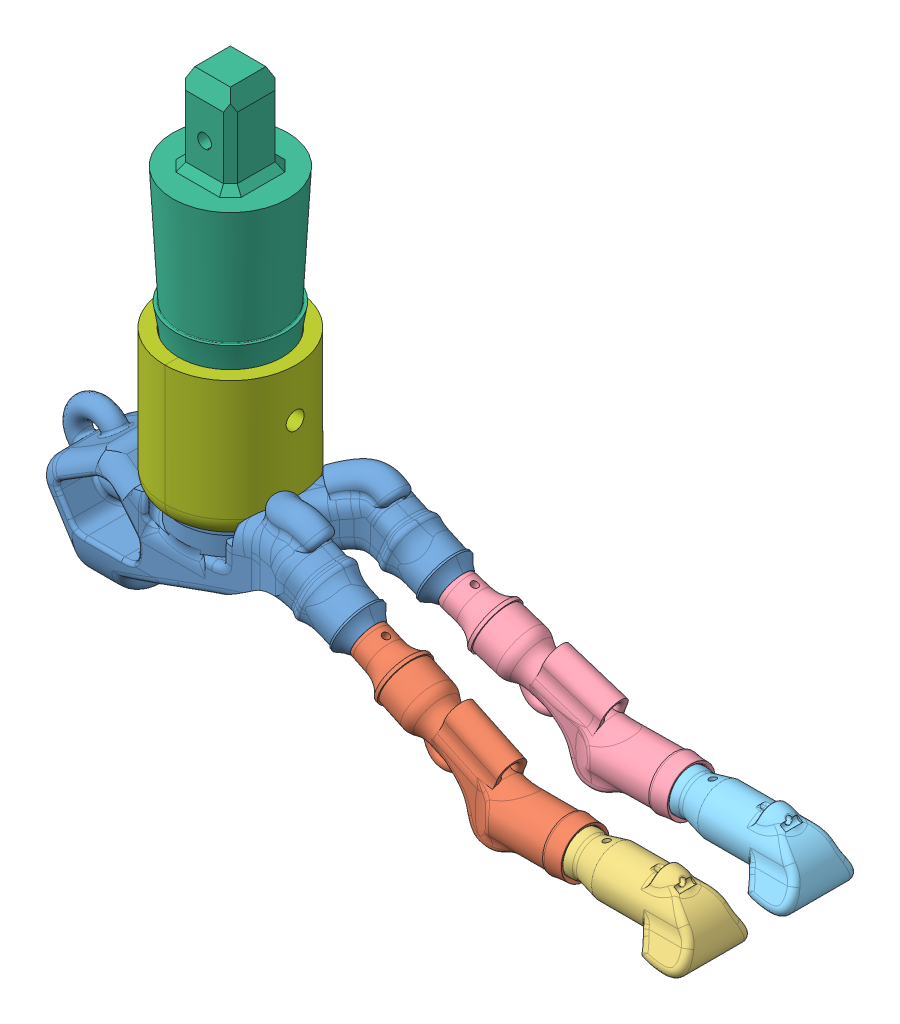
SolidWorks assembly Foot, configuration Default. Lengths in mm.
Overall size (260.5 189.24 79.33).
8 component instances, 7 part files, 12 mates.
Components (placement in the parent):
- Talus - New-1: Talus - New [Default] at origin size (131.32 65.14 51)
- Metatarsals-1: Metatarsals [Default] at (104.0952 -44.3034 18.1531) x (-0.929116 0.366544 -0.048875) z (0.042994 -0.024198 -0.998782) size (95.04 30.95 38.02)
- Phalanges-1: Phalanges [Default] at (172.2396 -55.1541 19.5999) size (57.16 24.44 28.69)
- Metatarsals - Left side-1: Metatarsals - Left side [Default] at (104.1326 -44.2161 -17.9587) x (-0.930097 0.364252 0.047332) z (-0.050841 -0.000045 -0.998707) size (95.04 30.95 38.02)
- Phalanges - Left side-1: Phalanges - Left side [Default] at (172.3053 -54.9301 -19.5095) size (57.16 24.44 28.69)
- Tibial End-1: Tibial End [Default] at (0 -22 0) x (0 0 1) z (-1 0 0) size (42.45 113.08 48.21)
- Sleeve-4: Sleeve [Default] at (0 -22.86 0) x (-1 0 0) z (0 0 -1) size (26.42 52.07 48.26)
- Sleeve-5: Sleeve [Default] at (0 -22.86 0) size (26.42 52.07 48.26)
Mates (geometry in assembly coordinates):
- Concentric1: concentric: sphere of Metatarsals-1; sphere of Talus - New-1
- Concentric2: concentric: sphere of Phalanges-1; sphere of Metatarsals-1
- Concentric3: concentric: sphere of Talus - New-1; sphere of Metatarsals - Left side-1
- Concentric4: concentric: sphere of Phalanges - Left side-1; sphere of Metatarsals - Left side-1
- Parallel4: parallel aligned: plane of Talus - New-1 through (0 0 17.78) normal (0 0 1); plane of Tibial End-1 through (-9.525 111.35 9.525) normal (0 0 1)
- LimitAngle3: limit planar angle = 1.570796 rad anti-aligned: plane of Tibial End-1 through (9.525 111.35 9.525) normal (1 0 0); plane of assembly through (0 0 0) normal (0 1 0)
- Concentric5: concentric aligned: cylinder of Tibial End-1 through (21.1996 10.2589 0) axis (-1 0 0) radius 3.302; cylinder of Sleeve-5 through (38.608 10.2589 0) axis (-1 0 0) radius 3.302
- Coincident13: coincident aligned: plane of Sleeve-4 through (0 27.94 0) normal (0 1 0); plane of Sleeve-5 through (0 27.94 0) normal (0 1 0)
- Concentric6: concentric anti-aligned: circle of Tibial End-1; circle of Sleeve-5
- Coincident15: coincident anti-aligned: plane of Sleeve-4 through (0 -22.86 0) normal (1 0 0); plane of Sleeve-5 through (0 -22.86 0) normal (-1 0 0)
- Concentric7: concentric anti-aligned: circle of Talus - New-1; circle of Tibial End-1
- Coincident18: coincident anti-aligned: plane of Talus - New-1 through (0 -24.13 0) normal (0 1 0); circle of Sleeve-4
